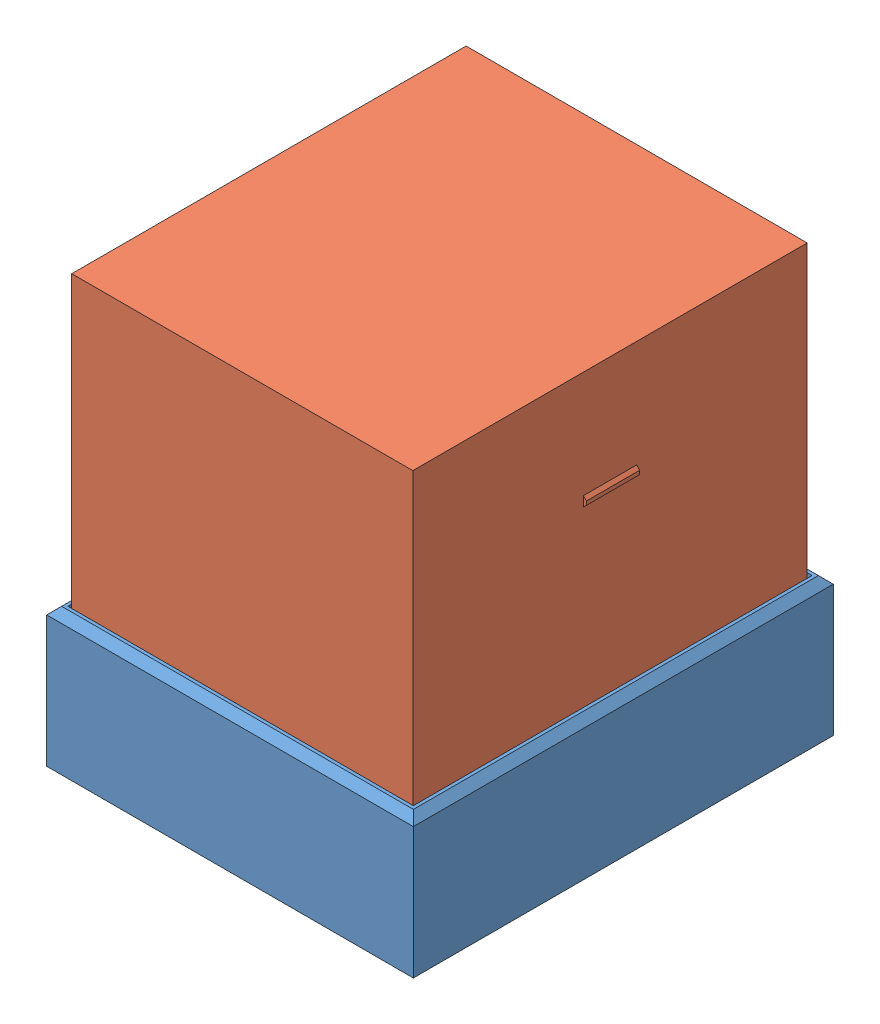
SolidWorks assembly Assem1, configuration Default. Lengths in mm.
Overall size (87.38 101.6 100.08).
2 component instances, 2 part files, 3 mates.
Components (placement in the parent):
- Deck Box Lid - C Type-1: Deck Box Lid - C Type [with Poneglyph] at (22.6406 38.945 93.2691) size (87.38 33.02 100.08)
- Deck Box - C Type-1: Deck Box - C Type [Sides For Designs] at (42.0046 135.465 -63.2082) x (-1 0 0) z (0 0 1) size (82.74 99.06 93.98)
Mates (geometry in assembly coordinates):
- Coincident1: coincident anti-aligned: plane of Deck Box Lid - C Type-1 through (22.6406 38.945 93.2691) normal (0 1 0); plane of Deck Box - C Type-1 through (42.0046 38.945 -63.7162) normal (0 -1 0)
- Distance2: distance = 0.381 mm anti-aligned: plane of Deck Box - C Type-1 through (-5.8955 38.945 -63.2082) normal (-1 0 0); plane of Deck Box Lid - C Type-1 through (-6.2765 69.425 93.2691) normal (1 0 0)
- Distance3: distance = 0.508 mm anti-aligned: plane of Deck Box Lid - C Type-1 through (22.6406 69.425 26.448) normal (0 0 1); plane of Deck Box - C Type-1 through (42.0046 38.945 26.956) normal (0 0 -1)
